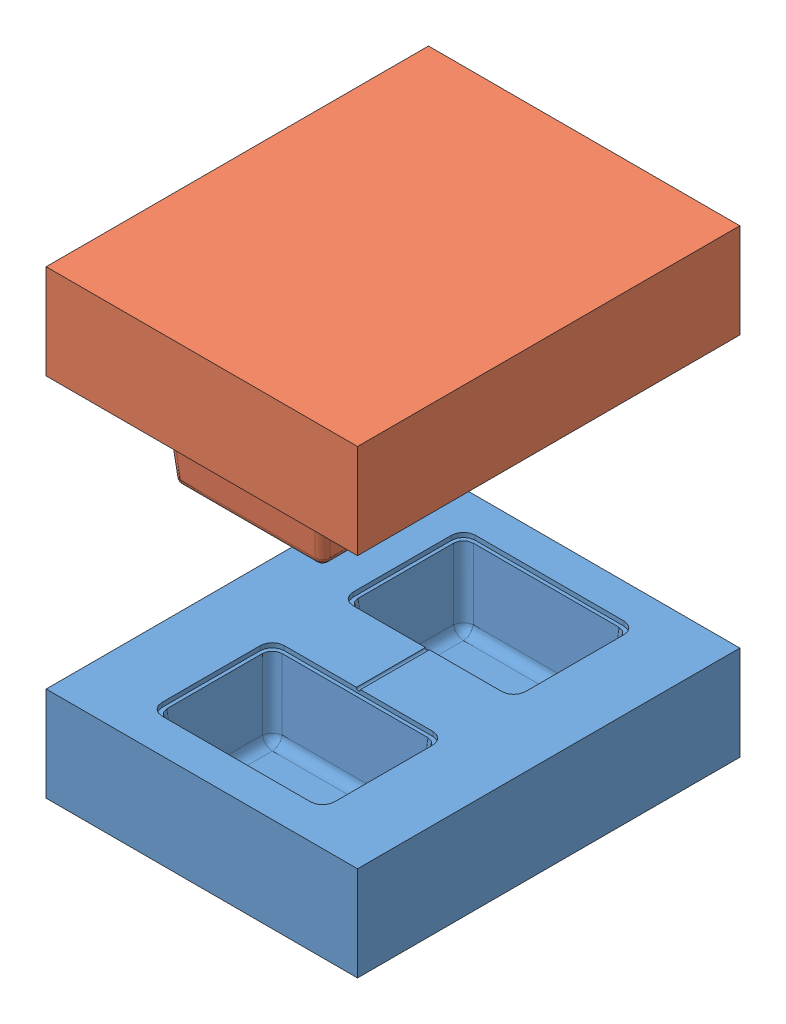
SolidWorks assembly Montagem2, configuration Valor predeterminado. Lengths in mm.
Overall size (316 467.16 388).
2 component instances, 2 part files, 6 mates.
Components (placement in the parent):
- Cavidade dupla do Pote--1: Cavidade dupla do Pote- [Valor predeterminado] at (0 -42 -97) size (316 96 388)
- Macho duplo do Pote--1: Macho duplo do Pote- [Valor predeterminado] at (0 233.1597 -97) size (316 173 388)
Mates (geometry in assembly coordinates):
- Coincidente1: coincident aligned: plane of Cavidade dupla do Pote--1 through (87.5 0 -47) normal (0 1 0); plane of assembly
- Distância1: distance = 158 mm aligned: plane of assembly; plane of Cavidade dupla do Pote--1 through (158 96 194) normal (1 0 0)
- Distância2: distance = 194 mm aligned: plane of Cavidade dupla do Pote--1 through (158 96 194) normal (0 0 1); plane of assembly
- Coincidente4: coincident aligned: plane of Cavidade dupla do Pote--1 through (158 96 194) normal (0 0 1); plane of Macho duplo do Pote--1 through (158 371.1597 194) normal (0 0 1)
- Coincidente5: coincident aligned: plane of Cavidade dupla do Pote--1 through (158 96 194) normal (1 0 0); plane of Macho duplo do Pote--1 through (158 371.1597 194) normal (1 0 0)
- DistânciaLimite1: limit distance = 275.1597 mm anti-aligned: plane of Macho duplo do Pote--1 through (87.5 275.1597 -47) normal (0 -1 0); plane of Cavidade dupla do Pote--1 through (87.5 0 -47) normal (0 1 0)
